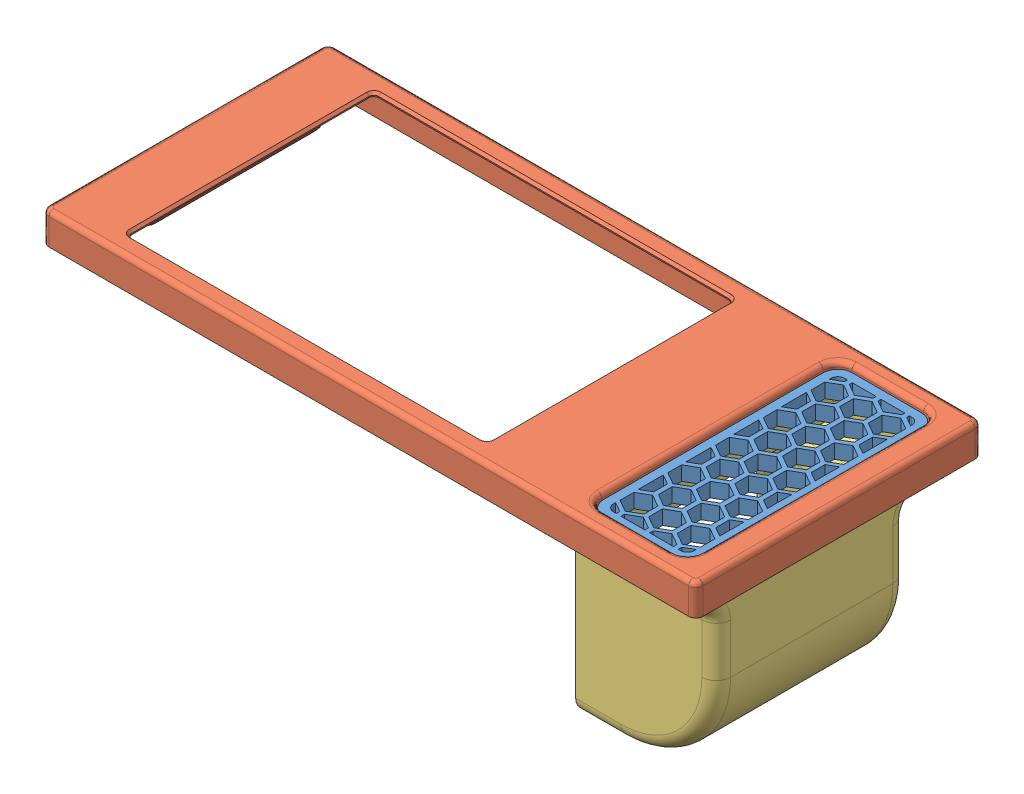
SolidWorks assembly Assem2, configuration Default. Lengths in mm.
Overall size (137 46.5 60).
3 component instances, 3 part files, 7 mates.
Components (placement in the parent):
- oven_airtake-1: oven_airtake [Default] at (53.7897 51.8865 102.0435) size (20.6 3 52.05)
- fur faceplate-1: fur faceplate [Default] at (-51.4103 45.8865 101.8435) x (-1 0 0) z (0 0 1) size (137 6.5 60)
- oven_fan-1: oven_fan [Default] at (-9.4103 43.8865 127.4167) x (0 0 -1) z (0 1 0) size (51.8 29.45 44.5)
Mates (geometry in assembly coordinates):
- Coincident2: coincident anti-aligned: plane of oven_airtake-1 through (11.5897 41.8865 78.8167) normal (1 0 0); plane of fur faceplate-1 through (11.5897 45.8865 75.6167) normal (-1 0 0)
- Parallel1: parallel anti-aligned: plane of oven_airtake-1 through (-6.2103 41.8865 76.0167) normal (0 0 -1); plane of fur faceplate-1 through (11.5897 45.8865 75.6167) normal (0 0 1)
- Coincident4: coincident anti-aligned: plane of oven_airtake-1 through (8.7897 41.8865 128.0704) normal (0 0 1); plane of fur faceplate-1 through (11.5897 45.8865 128.0704) normal (0 0 -1)
- Coincident5: coincident: plane of oven_airtake-1 through (122.2897 44.8865 67.6541) normal (0 1 0); line of fur faceplate-1 through (11.5897 44.8865 125.0704) axis (0 0 -1)
- Coincident6: coincident: plane of fur faceplate-1 through (-51.4103 39.3865 101.8435) normal (0 -1 0); plane of oven_fan-1 through (-9.4103 39.3865 75.6167) normal (0 1 0)
- Coincident7: coincident: plane of fur faceplate-1 through (11.5897 45.8865 75.6167) normal (0 0 1); plane of oven_fan-1 through (-9.4103 43.8865 75.6167) normal (0 0 -1)
- Coincident8: coincident anti-aligned: plane of fur faceplate-1 through (-9.4103 45.8865 75.6167) normal (1 0 0); plane of oven_fan-1 through (-9.4103 43.8865 75.6167) normal (-1 0 0)
